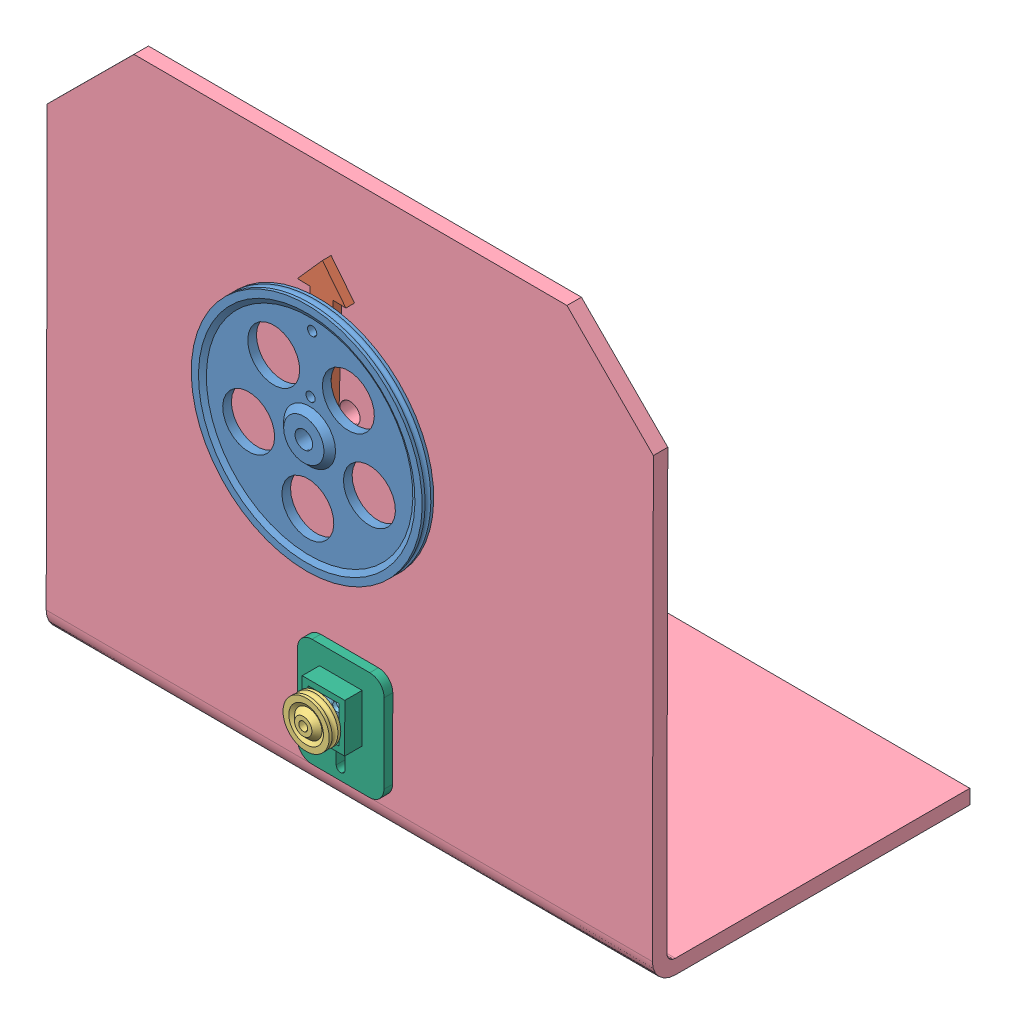
SolidWorks assembly assembly, configuration Default. Lengths in mm.
Overall size (210.45 190.49 126).
6 component instances, 6 part files, 14 mates.
Components (placement in the parent):
- arrow_gear-1: arrow_gear [Default] at (16.1113 -9.6776 58.8269) x (0.99961 -0.027931 0) z (0 0 1) size (80 80 5)
- arrow_head-1: arrow_head [Default] at (16.2155 -5.9488 56.8269) x (-0.99961 0.027931 0) z (-0.027931 -0.99961 0) size (16.78 3 45)
- motor_gear-1: motor_gear [Default] at (15.909 -95.8023 58.8269) x (0.287296 0.957842 0) z (0 0 1) size (16 16 5)
- base-1: base [Default] at (120.8292 -129.9238 45.8269) x (-0.999997 0.002348 0) z (0 0 -1) size (210 190 110)
- motor-1: motor [Predeterminado] at (15.909 -95.8023 25.8269) x (0.999997 -0.002348 0) z (-0.002348 -0.999997 0) size (10 25.8 12)
- motor_bracket-1: motor_bracket [Default] at (15.9096 -95.5523 45.8269) x (0.999997 -0.002348 0) z (-0.002348 -0.999997 0) size (30 9 37.5)
Mates (geometry in assembly coordinates):
- Concentric1: concentric anti-aligned: cylinder of arrow_gear-1 through (16.4464 2.3177 61.8269) axis (0 0 -1) radius 1.6; cylinder of arrow_head-1 through (16.4464 2.3177 53.8269) axis (0 0 1) radius 1.6
- Concentric2: concentric anti-aligned: cylinder of arrow_gear-1 through (17.0051 22.3099 61.8269) axis (0 0 -1) radius 1.6; cylinder of arrow_head-1 through (17.0051 22.3099 53.8269) axis (0 0 1) radius 1.6
- Coincident1: coincident anti-aligned: plane of arrow_gear-1 through (16.1113 -9.6776 56.8269) normal (0 0 -1); plane of arrow_head-1 through (16.2155 -5.9488 56.8269) normal (0 0 1)
- Coincident2: coincident aligned: plane of arrow_gear-1 through (16.1113 -9.6776 56.8269) normal (0 0 -1); plane of motor_gear-1 through (15.909 -95.8023 56.8269) normal (0 0 -1)
- Concentric3: concentric aligned: cylinder of arrow_gear-1 through (16.1113 -9.6776 56.8269) axis (0 0 1) radius 3.05; cylinder of base-1 through (16.1113 -9.6776 -64.1731) axis (0 0 1) radius 3.5
- Coincident3: coincident anti-aligned: plane of base-1 through (10.8765 -109.6656 -64.1731) normal (0.999997 -0.002348 0); plane of motor-1 through (10.895 -101.7906 49.8269) normal (-0.999997 0.002348 0)
- Parallel1: parallel anti-aligned: plane of base-1 through (10.8765 -109.6656 -64.1731) normal (0.002348 0.999997 0); plane of motor-1 through (20.8949 -101.8141 49.8269) normal (-0.002348 -0.999997 0)
- Concentric4: concentric anti-aligned: cylinder of motor_gear-1 through (15.909 -95.8023 56.8269) axis (0 0 1) radius 1.55; cylinder of motor-1 through (15.909 -95.8023 50.1269) axis (0 0 -1) radius 1.5
- Coincident5: coincident aligned: line of base-1 through (10.9352 -84.6656 40.8269) axis (-0.002348 -0.999997 0); line of motor-1 through (10.9208 -90.7906 40.8269) axis (-0.002348 -0.999997 0)
- Coincident6: coincident anti-aligned: plane of base-1 through (-88.7241 60.5688 45.8269) normal (0 0 1); plane of motor_bracket-1 through (15.9096 -95.5523 45.8269) normal (0 0 -1)
- Distance1: distance = 11 mm anti-aligned: plane of base-1 through (-88.7241 60.5688 45.8269) normal (0 0 1); plane of motor_gear-1 through (15.909 -95.8023 56.8269) normal (0 0 -1)
- Coincident9: coincident anti-aligned: plane of motor-1 through (10.9231 -89.7906 49.8269) normal (0.002348 0.999997 0); plane of motor_bracket-1 through (10.5481 -89.7897 48.8269) normal (-0.002348 -0.999997 0)
- BeltMate1: belt = 16 : 80 mm: circle of arrow_gear-1; circle of motor_gear-1
- Concentric5: concentric anti-aligned: cylinder of base-1 through (15.8647 -114.6773 -64.1731) axis (0 0 1) radius 1.6; cylinder of motor_bracket-1 through (15.8647 -114.6773 48.8269) axis (0 0 -1) radius 1.5375
